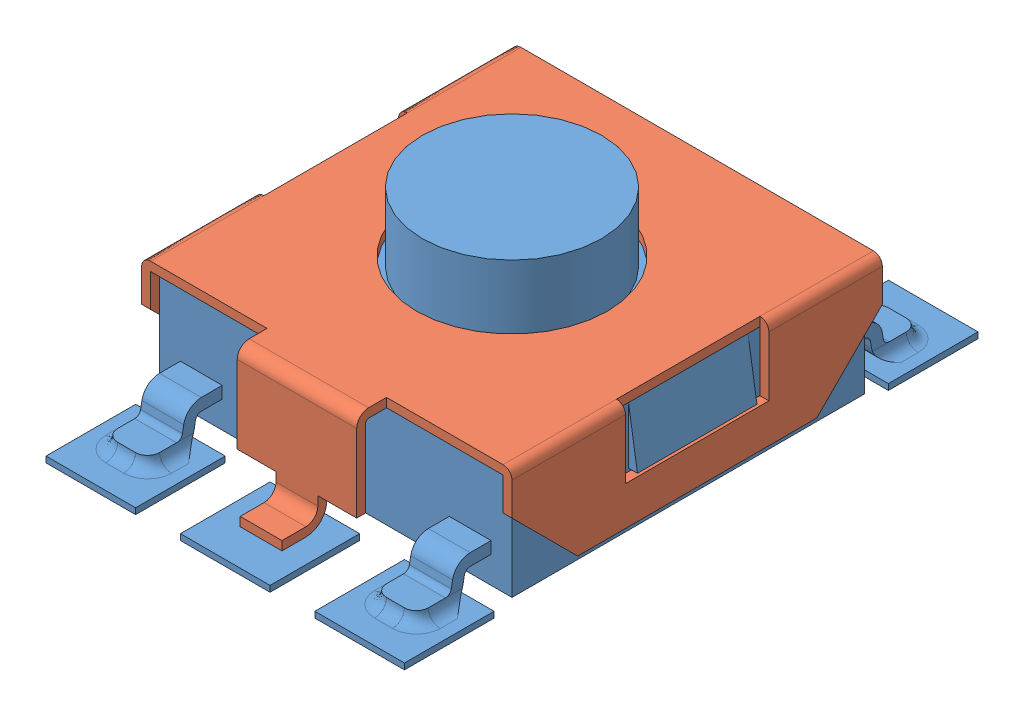
SolidWorks assembly RESET BUTTON.SL100001-10001-3-0ASM, configuration Default. Lengths in mm.
Overall size (6.2 3.1 9.6).
2 component instances, 2 part files, 6 mates.
Components (placement in the parent):
- RESET CORE.SL100001-10001-3-0PRT-1: RESET CORE.SL100001-10001-3-0PRT [Default] at (0 0.1 0) x (-1 0 0) z (0 0 -1) size (6.2 3.1 9.6)
- RESET.SL100001-10001-3-0PRT-1: RESET.SL100001-10001-3-0PRT [Default] at (0 0.1 0) x (0 0 1) z (-1 0 0) size (7.3 2 6.2)
Mates (geometry in assembly coordinates):
- Coincident4: coincident anti-aligned: plane of RESET CORE.SL100001-10001-3-0PRT-1 through (0 0.1 0) normal (0 0 -1); plane of assembly
- Coincident5: coincident anti-aligned: plane of RESET CORE.SL100001-10001-3-0PRT-1 through (0 0.1 0) normal (-1 0 0); plane of assembly through (0 0 0) normal (1 0 0)
- Coincident6: coincident anti-aligned: plane of RESET CORE.SL100001-10001-3-0PRT-1 through (0 0 0) normal (0 -1 0); plane of assembly through (0 0 0) normal (0 1 0)
- Coincident7: coincident aligned: plane of RESET.SL100001-10001-3-0PRT-1 through (0 0.1 0) normal (0 0 1); plane of assembly
- Coincident9: coincident anti-aligned: plane of RESET.SL100001-10001-3-0PRT-1 through (0 0.1 0) normal (-1 0 0); plane of assembly through (0 0 0) normal (1 0 0)
- Coincident10: coincident aligned: plane of RESET CORE.SL100001-10001-3-0PRT-1; plane of RESET.SL100001-10001-3-0PRT-1
